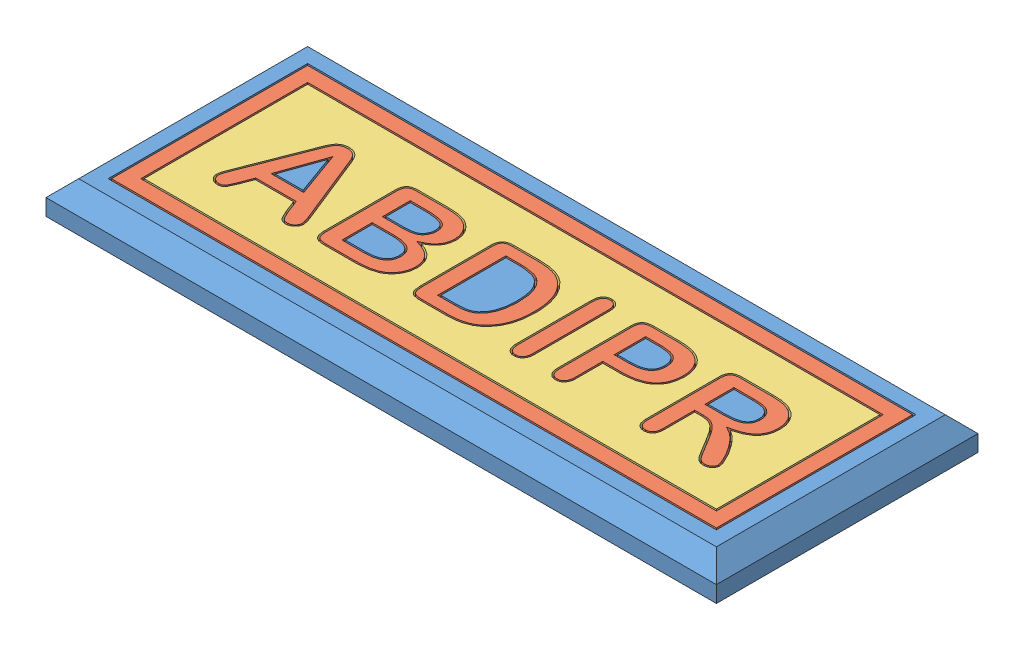
SolidWorks assembly three_part_test, configuration Default. Lengths in mm.
Overall size (41 2.01 16).
3 component instances, 3 part files, 6 mates.
Components (placement in the parent):
- three_part_test_bottom-1: three_part_test_bottom [Default] at origin size (41 2 16)
- three_part_test_middle-1: three_part_test_middle [Default] at (0 1 0) size (37 1.02 12)
- three_part_test_top-1: three_part_test_top [Default] at (0 1.5 0) size (35 0.5 10)
Mates (geometry in assembly coordinates):
- Coincident1: coincident aligned: plane of three_part_test_middle-1 through (0 1 0) normal (0 0 1); plane of assembly through (0 0 0) normal (0 0 1)
- Coincident2: coincident aligned: plane of three_part_test_top-1 through (0 1.5 0) normal (0 0 1); plane of assembly through (0 0 0) normal (0 0 1)
- Coincident3: coincident aligned: plane of three_part_test_middle-1 through (0 1 0) normal (1 0 0); plane of assembly through (0 0 0) normal (1 0 0)
- Coincident4: coincident aligned: plane of three_part_test_top-1 through (0 1.5 0) normal (1 0 0); plane of assembly through (0 0 0) normal (1 0 0)
- Coincident5: coincident aligned: plane of three_part_test_bottom-1 through (0 2 0) normal (0 1 0); plane of three_part_test_middle-1 through (0 2 0) normal (0 1 0)
- Coincident6: coincident aligned: plane of three_part_test_bottom-1 through (0 2 0) normal (0 1 0); plane of three_part_test_top-1 through (0 2 0) normal (0 1 0)
